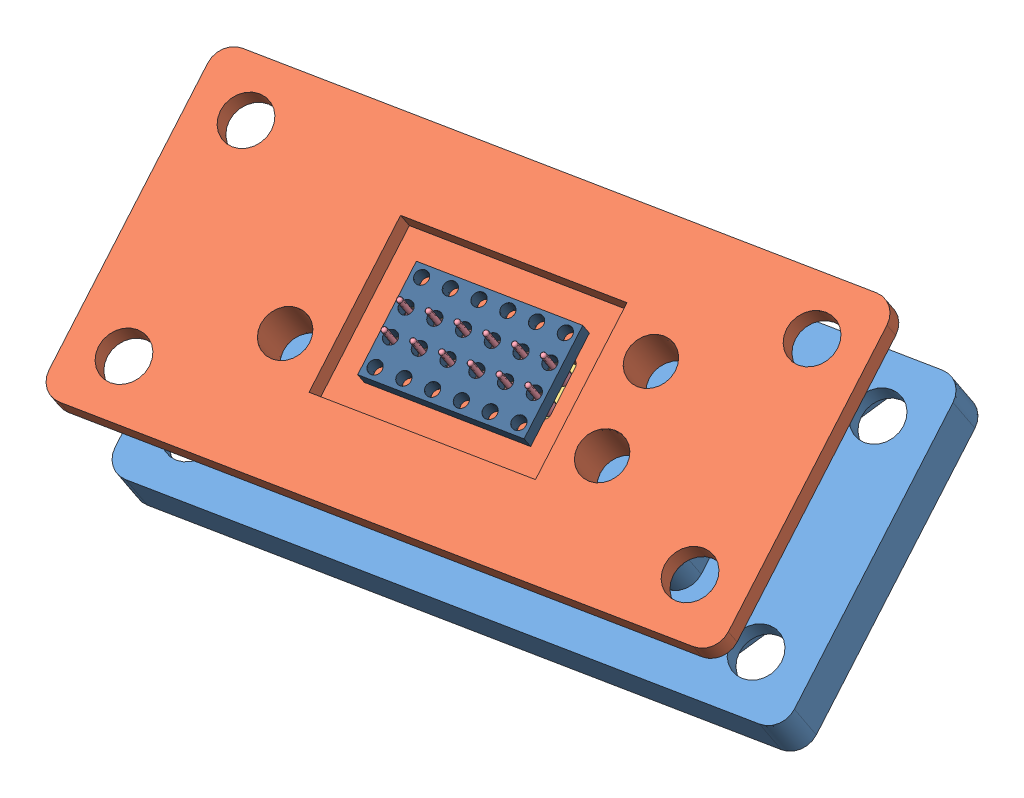
SolidWorks assembly Pogo_Fixture_Assembly, configuration Default. Lengths in mm.
Overall size (65.95 34.01 47.24).
138 component instances, 16 part files, 25 mates.
Components (placement in the parent):
- Pogo_Fixture_Male-2: Pogo_Fixture_Male [Default] at (19.7314 -83.9194 -57.5344) x (0.980151 -0.002673 -0.198236) z (-0.118444 -0.809738 -0.574714) size (60 30 8.18)
- Pogo_Fixture_Female-2: Pogo_Fixture_Female [Default] at (21.2786 -73.3423 -50.0273) x (-0.980151 0.002673 0.198236) z (0.118444 0.809738 0.574714) size (60 30 5.17)
- mill-max-419-10-212-00-001000-1: mill-max-419-10-212-00-001000 [Default] at (13.2092 -75.2259 -53.0027) x (0.980151 -0.002673 -0.198236) z (-0.158982 0.586786 -0.793982) size (15.24 7.37 5.08)
  - mill-max-419-10-212-00-001000_P4XX-21-010-00-000000-1: mill-max-419-10-212-00-001000_P4XX-21-010-00-000000 [Default] at origin size (15.24 2.79 5.08)
  - mill-max-419-10-212-00-001000_1942-1: mill-max-419-10-212-00-001000_1942 [Default] at (0.9644 0 -1.27) x (0 -1 0) z (0 0 1) size (7.37 1.78 1.78)
  - mill-max-419-10-212-00-001000_1942-2: mill-max-419-10-212-00-001000_1942 [Default] at (0.9644 0 -3.81) x (0 -1 0) z (0 0 1) size (7.37 1.78 1.78)
  - mill-max-419-10-212-00-001000_1942-3: mill-max-419-10-212-00-001000_1942 [Default] at (3.5044 0 -3.81) x (0 -1 0) z (0 0 1) size (7.37 1.78 1.78)
  - mill-max-419-10-212-00-001000_1942-4: mill-max-419-10-212-00-001000_1942 [Default] at (3.5044 0 -1.27) x (0 -1 0) z (0 0 1) size (7.37 1.78 1.78)
  - mill-max-419-10-212-00-001000_1942-5: mill-max-419-10-212-00-001000_1942 [Default] at (6.0444 0 -3.81) x (0 -1 0) z (0 0 1) size (7.37 1.78 1.78)
  - mill-max-419-10-212-00-001000_1942-6: mill-max-419-10-212-00-001000_1942 [Default] at (8.5844 0 -3.81) x (0 -1 0) z (0 0 1) size (7.37 1.78 1.78)
  - mill-max-419-10-212-00-001000_1942-7: mill-max-419-10-212-00-001000_1942 [Default] at (11.1244 0 -3.81) x (0 -1 0) z (0 0 1) size (7.37 1.78 1.78)
  - mill-max-419-10-212-00-001000_1942-8: mill-max-419-10-212-00-001000_1942 [Default] at (13.6644 0 -3.81) x (0 -1 0) z (0 0 1) size (7.37 1.78 1.78)
  - mill-max-419-10-212-00-001000_1942-9: mill-max-419-10-212-00-001000_1942 [Default] at (6.0444 0 -1.27) x (0 -1 0) z (0 0 1) size (7.37 1.78 1.78)
  - mill-max-419-10-212-00-001000_1942-10: mill-max-419-10-212-00-001000_1942 [Default] at (8.5844 0 -1.27) x (0 -1 0) z (0 0 1) size (7.37 1.78 1.78)
  - mill-max-419-10-212-00-001000_1942-11: mill-max-419-10-212-00-001000_1942 [Default] at (11.1244 0 -1.27) x (0 -1 0) z (0 0 1) size (7.37 1.78 1.78)
  - mill-max-419-10-212-00-001000_1942-12: mill-max-419-10-212-00-001000_1942 [Default] at (13.6644 0 -1.27) x (0 -1 0) z (0 0 1) size (7.37 1.78 1.78)
- mill-max-818-22-012-10-000101-1: mill-max-818-22-012-10-000101 [Default] at (12.9898 -85.228 -53.9526) x (0.980151 -0.002673 -0.198236) z (0.158982 -0.586786 0.793982) size (15.24 8.23 5.08)
  - mill-max-818-22-012-10-000101_P4XX-28-010-00-090000-1: mill-max-818-22-012-10-000101_P4XX-28-010-00-090000 [Default] at origin size (15.24 2.79 5.08)
  - mill-max-818-22-012-10-000101_0963-0-1: mill-max-818-22-012-10-000101_0963-0 [Default] at (0.9644 -4.953 -1.27) x (0 1 0) z (0 0 1) size (4.04 1.31 1.31)
  - mill-max-818-22-012-10-000101_0954-0-1: mill-max-818-22-012-10-000101_0954-0 [Default] at (0.9644 -3.2004 -1.27) x (0 1 0) z (-0.856247 0 0.516567) size (5.03 1.83 1.83)
  - mill-max-818-22-012-10-000101_0918-X-1: mill-max-818-22-012-10-000101_0918-X [Default] at (0.9644 -1.2192 -1.27) x (0 1 0) z (0 0 1) size (4.5 1.25 1.25)
  - mill-max-818-22-012-10-000101_6875-0-00-00-75-XX-43-0C-1: mill-max-818-22-012-10-000101_6875-0-00-00-75-XX-43-0C [Default] at (0.9644 0.6355 -1.27) x (-0.956034 0 -0.293257) z (0 -1 0) size (0.2 0.07 3.45)
  - mill-max-818-22-012-10-000101_0963-0-2: mill-max-818-22-012-10-000101_0963-0 [Default] at (0.9644 -4.953 -3.81) x (0 1 0) z (0 0 1) size (4.04 1.31 1.31)
  - mill-max-818-22-012-10-000101_0954-0-2: mill-max-818-22-012-10-000101_0954-0 [Default] at (0.9644 -3.2004 -3.81) x (0 1 0) z (0.135119 0 0.990829) size (5.03 1.83 1.83)
  - mill-max-818-22-012-10-000101_0918-X-2: mill-max-818-22-012-10-000101_0918-X [Default] at (0.9644 -1.2192 -3.81) x (0 1 0) z (0.012366 0 0.999924) size (4.5 1.25 1.25)
  - mill-max-818-22-012-10-000101_6875-0-00-00-75-XX-43-0C-2: mill-max-818-22-012-10-000101_6875-0-00-00-75-XX-43-0C [Default] at (0.9644 0.6358 -1.27) x (-0.954499 0 -0.298214) z (0 -1 0) size (0.2 0.07 3.45)
  - mill-max-818-22-012-10-000101_6875-0-00-00-75-XX-43-0C-3: mill-max-818-22-012-10-000101_6875-0-00-00-75-XX-43-0C [Default] at (3.5044 0.6358 -1.27) x (-0.954499 0 -0.298214) z (0 -1 0) size (0.2 0.07 3.45)
  - mill-max-818-22-012-10-000101_0918-X-3: mill-max-818-22-012-10-000101_0918-X [Default] at (3.5044 -1.2192 -3.81) x (0 1 0) z (0.012366 0 0.999924) size (4.5 1.25 1.25)
  - mill-max-818-22-012-10-000101_0954-0-3: mill-max-818-22-012-10-000101_0954-0 [Default] at (3.5044 -3.2004 -3.81) x (0 1 0) z (0.135119 0 0.990829) size (5.03 1.83 1.83)
  - mill-max-818-22-012-10-000101_0963-0-3: mill-max-818-22-012-10-000101_0963-0 [Default] at (3.5044 -4.953 -3.81) x (0 1 0) z (0 0 1) size (4.04 1.31 1.31)
  - mill-max-818-22-012-10-000101_6875-0-00-00-75-XX-43-0C-4: mill-max-818-22-012-10-000101_6875-0-00-00-75-XX-43-0C [Default] at (3.5044 0.6355 -1.27) x (-0.956034 0 -0.293257) z (0 -1 0) size (0.2 0.07 3.45)
  - mill-max-818-22-012-10-000101_0918-X-4: mill-max-818-22-012-10-000101_0918-X [Default] at (3.5044 -1.2192 -1.27) x (0 1 0) z (0 0 1) size (4.5 1.25 1.25)
  - mill-max-818-22-012-10-000101_0954-0-4: mill-max-818-22-012-10-000101_0954-0 [Default] at (3.5044 -3.2004 -1.27) x (0 1 0) z (-0.856247 0 0.516567) size (5.03 1.83 1.83)
  - mill-max-818-22-012-10-000101_0963-0-4: mill-max-818-22-012-10-000101_0963-0 [Default] at (3.5044 -4.953 -1.27) x (0 1 0) z (0 0 1) size (4.04 1.31 1.31)
  - mill-max-818-22-012-10-000101_6875-0-00-00-75-XX-43-0C-5: mill-max-818-22-012-10-000101_6875-0-00-00-75-XX-43-0C [Default] at (6.0444 0.6358 -1.27) x (-0.954499 0 -0.298214) z (0 -1 0) size (0.2 0.07 3.45)
  - mill-max-818-22-012-10-000101_6875-0-00-00-75-XX-43-0C-6: mill-max-818-22-012-10-000101_6875-0-00-00-75-XX-43-0C [Default] at (8.5844 0.6358 -1.27) x (-0.954499 0 -0.298214) z (0 -1 0) size (0.2 0.07 3.45)
  - mill-max-818-22-012-10-000101_6875-0-00-00-75-XX-43-0C-7: mill-max-818-22-012-10-000101_6875-0-00-00-75-XX-43-0C [Default] at (11.1244 0.6358 -1.27) x (-0.954499 0 -0.298214) z (0 -1 0) size (0.2 0.07 3.45)
  - mill-max-818-22-012-10-000101_6875-0-00-00-75-XX-43-0C-8: mill-max-818-22-012-10-000101_6875-0-00-00-75-XX-43-0C [Default] at (13.6644 0.6358 -1.27) x (-0.954499 0 -0.298214) z (0 -1 0) size (0.2 0.07 3.45)
  - mill-max-818-22-012-10-000101_0918-X-5: mill-max-818-22-012-10-000101_0918-X [Default] at (6.0444 -1.2192 -3.81) x (0 1 0) z (0.012366 0 0.999924) size (4.5 1.25 1.25)
  - mill-max-818-22-012-10-000101_0918-X-6: mill-max-818-22-012-10-000101_0918-X [Default] at (8.5844 -1.2192 -3.81) x (0 1 0) z (0.012366 0 0.999924) size (4.5 1.25 1.25)
  - mill-max-818-22-012-10-000101_0918-X-7: mill-max-818-22-012-10-000101_0918-X [Default] at (11.1244 -1.2192 -3.81) x (0 1 0) z (0.012366 0 0.999924) size (4.5 1.25 1.25)
  - mill-max-818-22-012-10-000101_0918-X-8: mill-max-818-22-012-10-000101_0918-X [Default] at (13.6644 -1.2192 -3.81) x (0 1 0) z (0.012366 0 0.999924) size (4.5 1.25 1.25)
  - mill-max-818-22-012-10-000101_0954-0-5: mill-max-818-22-012-10-000101_0954-0 [Default] at (6.0444 -3.2004 -3.81) x (0 1 0) z (0.135119 0 0.990829) size (5.03 1.83 1.83)
  - mill-max-818-22-012-10-000101_0954-0-6: mill-max-818-22-012-10-000101_0954-0 [Default] at (8.5844 -3.2004 -3.81) x (0 1 0) z (0.135119 0 0.990829) size (5.03 1.83 1.83)
  - mill-max-818-22-012-10-000101_0954-0-7: mill-max-818-22-012-10-000101_0954-0 [Default] at (11.1244 -3.2004 -3.81) x (0 1 0) z (0.135119 0 0.990829) size (5.03 1.83 1.83)
  - mill-max-818-22-012-10-000101_0954-0-8: mill-max-818-22-012-10-000101_0954-0 [Default] at (13.6644 -3.2004 -3.81) x (0 1 0) z (0.135119 0 0.990829) size (5.03 1.83 1.83)
  - mill-max-818-22-012-10-000101_0963-0-5: mill-max-818-22-012-10-000101_0963-0 [Default] at (6.0444 -4.953 -3.81) x (0 1 0) z (0 0 1) size (4.04 1.31 1.31)
  - mill-max-818-22-012-10-000101_0963-0-6: mill-max-818-22-012-10-000101_0963-0 [Default] at (8.5844 -4.953 -3.81) x (0 1 0) z (0 0 1) size (4.04 1.31 1.31)
  - mill-max-818-22-012-10-000101_0963-0-7: mill-max-818-22-012-10-000101_0963-0 [Default] at (11.1244 -4.953 -3.81) x (0 1 0) z (0 0 1) size (4.04 1.31 1.31)
  - mill-max-818-22-012-10-000101_0963-0-8: mill-max-818-22-012-10-000101_0963-0 [Default] at (13.6644 -4.953 -3.81) x (0 1 0) z (0 0 1) size (4.04 1.31 1.31)
  - mill-max-818-22-012-10-000101_6875-0-00-00-75-XX-43-0C-9: mill-max-818-22-012-10-000101_6875-0-00-00-75-XX-43-0C [Default] at (6.0444 0.6355 -1.27) x (-0.956034 0 -0.293257) z (0 -1 0) size (0.2 0.07 3.45)
  - mill-max-818-22-012-10-000101_6875-0-00-00-75-XX-43-0C-10: mill-max-818-22-012-10-000101_6875-0-00-00-75-XX-43-0C [Default] at (8.5844 0.6355 -1.27) x (-0.956034 0 -0.293257) z (0 -1 0) size (0.2 0.07 3.45)
  - mill-max-818-22-012-10-000101_6875-0-00-00-75-XX-43-0C-11: mill-max-818-22-012-10-000101_6875-0-00-00-75-XX-43-0C [Default] at (11.1244 0.6355 -1.27) x (-0.956034 0 -0.293257) z (0 -1 0) size (0.2 0.07 3.45)
  - mill-max-818-22-012-10-000101_6875-0-00-00-75-XX-43-0C-12: mill-max-818-22-012-10-000101_6875-0-00-00-75-XX-43-0C [Default] at (13.6644 0.6355 -1.27) x (-0.956034 0 -0.293257) z (0 -1 0) size (0.2 0.07 3.45)
  - mill-max-818-22-012-10-000101_0918-X-9: mill-max-818-22-012-10-000101_0918-X [Default] at (6.0444 -1.2192 -1.27) x (0 1 0) z (0 0 1) size (4.5 1.25 1.25)
  - mill-max-818-22-012-10-000101_0918-X-10: mill-max-818-22-012-10-000101_0918-X [Default] at (8.5844 -1.2192 -1.27) x (0 1 0) z (0 0 1) size (4.5 1.25 1.25)
  - mill-max-818-22-012-10-000101_0918-X-11: mill-max-818-22-012-10-000101_0918-X [Default] at (11.1244 -1.2192 -1.27) x (0 1 0) z (0 0 1) size (4.5 1.25 1.25)
  - mill-max-818-22-012-10-000101_0918-X-12: mill-max-818-22-012-10-000101_0918-X [Default] at (13.6644 -1.2192 -1.27) x (0 1 0) z (0 0 1) size (4.5 1.25 1.25)
  - mill-max-818-22-012-10-000101_0954-0-9: mill-max-818-22-012-10-000101_0954-0 [Default] at (6.0444 -3.2004 -1.27) x (0 1 0) z (-0.856247 0 0.516567) size (5.03 1.83 1.83)
  - mill-max-818-22-012-10-000101_0954-0-10: mill-max-818-22-012-10-000101_0954-0 [Default] at (8.5844 -3.2004 -1.27) x (0 1 0) z (-0.856247 0 0.516567) size (5.03 1.83 1.83)
  - mill-max-818-22-012-10-000101_0954-0-11: mill-max-818-22-012-10-000101_0954-0 [Default] at (11.1244 -3.2004 -1.27) x (0 1 0) z (-0.856247 0 0.516567) size (5.03 1.83 1.83)
  - mill-max-818-22-012-10-000101_0954-0-12: mill-max-818-22-012-10-000101_0954-0 [Default] at (13.6644 -3.2004 -1.27) x (0 1 0) z (-0.856247 0 0.516567) size (5.03 1.83 1.83)
  - mill-max-818-22-012-10-000101_0963-0-9: mill-max-818-22-012-10-000101_0963-0 [Default] at (6.0444 -4.953 -1.27) x (0 1 0) z (0 0 1) size (4.04 1.31 1.31)
  - mill-max-818-22-012-10-000101_0963-0-10: mill-max-818-22-012-10-000101_0963-0 [Default] at (8.5844 -4.953 -1.27) x (0 1 0) z (0 0 1) size (4.04 1.31 1.31)
  - mill-max-818-22-012-10-000101_0963-0-11: mill-max-818-22-012-10-000101_0963-0 [Default] at (11.1244 -4.953 -1.27) x (0 1 0) z (0 0 1) size (4.04 1.31 1.31)
  - mill-max-818-22-012-10-000101_0963-0-12: mill-max-818-22-012-10-000101_0963-0 [Default] at (13.6644 -4.953 -1.27) x (0 1 0) z (0 0 1) size (4.04 1.31 1.31)
- Perf_Board-1: Perf_Board [Default] at (21.2786 -73.3423 -50.0273) x (-0.980151 0.002673 0.198236) z (-0.158982 0.586786 -0.793982) size (14.7 1.5 9.62)
- Perf_Board-2: Perf_Board [Default] at (19.3761 -86.3486 -59.2586) x (-0.980151 0.002673 0.198236) z (0.158982 -0.586786 0.793982) size (14.7 1.5 9.62)
- Dowel_Pin_93600A123-1: Dowel_Pin_93600A123 [93600A123] at (34.5158 -83.3889 -55.0648) x (0.118444 0.809738 0.574714) z (-0.037614 -0.574714 0.81749) size (7.2 4 4)
- Dowel_Pin_93600A123-2: Dowel_Pin_93600A123 [93600A123] at (7.0716 -83.3141 -49.5142) x (0.118444 0.809738 0.574714) z (-0.037614 -0.574714 0.81749) size (7.2 4 4)
- Dowel_Pin_93600A123-3: Dowel_Pin_93600A123 [93600A123] at (33.244 -78.6946 -61.4167) x (0.118444 0.809738 0.574714) z (-0.037614 -0.574714 0.81749) size (7.2 4 4)
- mill-max-823-22-016-10-004101-1: mill-max-823-22-016-10-004101 [Default] at (10.7814 -85.6809 -52.8594) x (0.980151 -0.002673 -0.198236) z (0.158982 -0.586786 0.793982) size (20.32 7.75 5.08)
  - mill-max-823-22-016-10-004101_P4XX-28-010-00-090000-1: mill-max-823-22-016-10-004101_P4XX-28-010-00-090000 [Default] at origin size (20.32 2.79 5.08)
  - mill-max-823-22-016-10-004101_0963-0-1: mill-max-823-22-016-10-004101_0963-0 [Default] at (0.9644 -4.953 -1.27) x (0 1 0) z (0 0 1) size (4.04 1.31 1.31)
  - mill-max-823-22-016-10-004101_0953-X-1: mill-max-823-22-016-10-004101_0953-X [Default] at (0.9644 -3.2004 -1.27) x (0 1 0) z (-0.980895 0 0.194537) size (2.69 1.83 1.83)
  - mill-max-823-22-016-10-004101_0918-X-1: mill-max-823-22-016-10-004101_0918-X [Default] at (0.9644 -1.1938 -1.27) x (0 1 0) z (0 0 1) size (3.99 1.25 1.25)
  - mill-max-823-22-016-10-004101_6875-0-00-00-75-XX-43-0C-1: mill-max-823-22-016-10-004101_6875-0-00-00-75-XX-43-0C [Default] at (0.9644 0.6557 -1.27) x (-0.956034 0 -0.293257) z (0 -1 0) size (0.2 0.07 3.45)
  - mill-max-823-22-016-10-004101_0963-0-2: mill-max-823-22-016-10-004101_0963-0 [Default] at (0.9644 -4.953 -3.81) x (0 1 0) z (0 0 1) size (4.04 1.31 1.31)
  - mill-max-823-22-016-10-004101_0953-X-2: mill-max-823-22-016-10-004101_0953-X [Default] at (0.9644 -3.2004 -3.81) x (0 1 0) z (0 0 1) size (2.69 1.83 1.83)
  - mill-max-823-22-016-10-004101_0918-X-2: mill-max-823-22-016-10-004101_0918-X [Default] at (0.9644 -1.1938 -3.81) x (0 1 0) z (0.012366 0 0.999924) size (3.99 1.25 1.25)
  - mill-max-823-22-016-10-004101_6875-0-00-00-75-XX-43-0C-2: mill-max-823-22-016-10-004101_6875-0-00-00-75-XX-43-0C [Default] at (0.9644 -2.5164 -3.81) x (-0.692815 0 0.721116) z (0 1 0) size (0.2 0.07 3.45)
  - mill-max-823-22-016-10-004101_6875-0-00-00-75-XX-43-0C-3: mill-max-823-22-016-10-004101_6875-0-00-00-75-XX-43-0C [Default] at (3.5044 -2.5164 -3.81) x (-0.692815 0 0.721116) z (0 1 0) size (0.2 0.07 3.45)
  - mill-max-823-22-016-10-004101_0918-X-3: mill-max-823-22-016-10-004101_0918-X [Default] at (3.5044 -1.1938 -3.81) x (0 1 0) z (0.012366 0 0.999924) size (3.99 1.25 1.25)
  - mill-max-823-22-016-10-004101_0953-X-3: mill-max-823-22-016-10-004101_0953-X [Default] at (3.5044 -3.2004 -3.81) x (0 1 0) z (0 0 1) size (2.69 1.83 1.83)
  - mill-max-823-22-016-10-004101_0963-0-3: mill-max-823-22-016-10-004101_0963-0 [Default] at (3.5044 -4.953 -3.81) x (0 1 0) z (0 0 1) size (4.04 1.31 1.31)
  - mill-max-823-22-016-10-004101_6875-0-00-00-75-XX-43-0C-4: mill-max-823-22-016-10-004101_6875-0-00-00-75-XX-43-0C [Default] at (3.5044 0.6557 -1.27) x (-0.956034 0 -0.293257) z (0 -1 0) size (0.2 0.07 3.45)
  - mill-max-823-22-016-10-004101_0918-X-4: mill-max-823-22-016-10-004101_0918-X [Default] at (3.5044 -1.1938 -1.27) x (0 1 0) z (0 0 1) size (3.99 1.25 1.25)
  - mill-max-823-22-016-10-004101_0953-X-4: mill-max-823-22-016-10-004101_0953-X [Default] at (3.5044 -3.2004 -1.27) x (0 1 0) z (-0.980895 0 0.194537) size (2.69 1.83 1.83)
  - mill-max-823-22-016-10-004101_0963-0-4: mill-max-823-22-016-10-004101_0963-0 [Default] at (3.5044 -4.953 -1.27) x (0 1 0) z (0 0 1) size (4.04 1.31 1.31)
  - mill-max-823-22-016-10-004101_6875-0-00-00-75-XX-43-0C-5: mill-max-823-22-016-10-004101_6875-0-00-00-75-XX-43-0C [Default] at (6.0444 -2.5164 -3.81) x (-0.692815 0 0.721116) z (0 1 0) size (0.2 0.07 3.45)
  - mill-max-823-22-016-10-004101_6875-0-00-00-75-XX-43-0C-6: mill-max-823-22-016-10-004101_6875-0-00-00-75-XX-43-0C [Default] at (8.5844 -2.5164 -3.81) x (-0.692815 0 0.721116) z (0 1 0) size (0.2 0.07 3.45)
  - mill-max-823-22-016-10-004101_6875-0-00-00-75-XX-43-0C-7: mill-max-823-22-016-10-004101_6875-0-00-00-75-XX-43-0C [Default] at (11.1244 -2.5164 -3.81) x (-0.692815 0 0.721116) z (0 1 0) size (0.2 0.07 3.45)
  - mill-max-823-22-016-10-004101_6875-0-00-00-75-XX-43-0C-8: mill-max-823-22-016-10-004101_6875-0-00-00-75-XX-43-0C [Default] at (13.6644 -2.5164 -3.81) x (-0.692815 0 0.721116) z (0 1 0) size (0.2 0.07 3.45)
  - mill-max-823-22-016-10-004101_6875-0-00-00-75-XX-43-0C-9: mill-max-823-22-016-10-004101_6875-0-00-00-75-XX-43-0C [Default] at (16.2044 -2.5164 -3.81) x (-0.692815 0 0.721116) z (0 1 0) size (0.2 0.07 3.45)
  - mill-max-823-22-016-10-004101_6875-0-00-00-75-XX-43-0C-10: mill-max-823-22-016-10-004101_6875-0-00-00-75-XX-43-0C [Default] at (18.7444 -2.5164 -3.81) x (-0.692815 0 0.721116) z (0 1 0) size (0.2 0.07 3.45)
  - mill-max-823-22-016-10-004101_0918-X-5: mill-max-823-22-016-10-004101_0918-X [Default] at (6.0444 -1.1938 -3.81) x (0 1 0) z (0.012366 0 0.999924) size (3.99 1.25 1.25)
  - mill-max-823-22-016-10-004101_0918-X-6: mill-max-823-22-016-10-004101_0918-X [Default] at (8.5844 -1.1938 -3.81) x (0 1 0) z (0.012366 0 0.999924) size (3.99 1.25 1.25)
  - mill-max-823-22-016-10-004101_0918-X-7: mill-max-823-22-016-10-004101_0918-X [Default] at (11.1244 -1.1938 -3.81) x (0 1 0) z (0.012366 0 0.999924) size (3.99 1.25 1.25)
  - mill-max-823-22-016-10-004101_0918-X-8: mill-max-823-22-016-10-004101_0918-X [Default] at (13.6644 -1.1938 -3.81) x (0 1 0) z (0.012366 0 0.999924) size (3.99 1.25 1.25)
  - mill-max-823-22-016-10-004101_0918-X-9: mill-max-823-22-016-10-004101_0918-X [Default] at (16.2044 -1.1938 -3.81) x (0 1 0) z (0.012366 0 0.999924) size (3.99 1.25 1.25)
  - mill-max-823-22-016-10-004101_0918-X-10: mill-max-823-22-016-10-004101_0918-X [Default] at (18.7444 -1.1938 -3.81) x (0 1 0) z (0.012366 0 0.999924) size (3.99 1.25 1.25)
  - mill-max-823-22-016-10-004101_0953-X-5: mill-max-823-22-016-10-004101_0953-X [Default] at (6.0444 -3.2004 -3.81) x (0 1 0) z (0 0 1) size (2.69 1.83 1.83)
  - mill-max-823-22-016-10-004101_0953-X-6: mill-max-823-22-016-10-004101_0953-X [Default] at (8.5844 -3.2004 -3.81) x (0 1 0) z (0 0 1) size (2.69 1.83 1.83)
  - mill-max-823-22-016-10-004101_0953-X-7: mill-max-823-22-016-10-004101_0953-X [Default] at (11.1244 -3.2004 -3.81) x (0 1 0) z (0 0 1) size (2.69 1.83 1.83)
  - mill-max-823-22-016-10-004101_0953-X-8: mill-max-823-22-016-10-004101_0953-X [Default] at (13.6644 -3.2004 -3.81) x (0 1 0) z (0 0 1) size (2.69 1.83 1.83)
  - mill-max-823-22-016-10-004101_0953-X-9: mill-max-823-22-016-10-004101_0953-X [Default] at (16.2044 -3.2004 -3.81) x (0 1 0) z (0 0 1) size (2.69 1.83 1.83)
  - mill-max-823-22-016-10-004101_0953-X-10: mill-max-823-22-016-10-004101_0953-X [Default] at (18.7444 -3.2004 -3.81) x (0 1 0) z (0 0 1) size (2.69 1.83 1.83)
  - mill-max-823-22-016-10-004101_0963-0-5: mill-max-823-22-016-10-004101_0963-0 [Default] at (6.0444 -4.953 -3.81) x (0 1 0) z (0 0 1) size (4.04 1.31 1.31)
  - mill-max-823-22-016-10-004101_0963-0-6: mill-max-823-22-016-10-004101_0963-0 [Default] at (8.5844 -4.953 -3.81) x (0 1 0) z (0 0 1) size (4.04 1.31 1.31)
  - mill-max-823-22-016-10-004101_0963-0-7: mill-max-823-22-016-10-004101_0963-0 [Default] at (11.1244 -4.953 -3.81) x (0 1 0) z (0 0 1) size (4.04 1.31 1.31)
  - mill-max-823-22-016-10-004101_0963-0-8: mill-max-823-22-016-10-004101_0963-0 [Default] at (13.6644 -4.953 -3.81) x (0 1 0) z (0 0 1) size (4.04 1.31 1.31)
  - mill-max-823-22-016-10-004101_0963-0-9: mill-max-823-22-016-10-004101_0963-0 [Default] at (16.2044 -4.953 -3.81) x (0 1 0) z (0 0 1) size (4.04 1.31 1.31)
  - mill-max-823-22-016-10-004101_0963-0-10: mill-max-823-22-016-10-004101_0963-0 [Default] at (18.7444 -4.953 -3.81) x (0 1 0) z (0 0 1) size (4.04 1.31 1.31)
  - mill-max-823-22-016-10-004101_6875-0-00-00-75-XX-43-0C-11: mill-max-823-22-016-10-004101_6875-0-00-00-75-XX-43-0C [Default] at (6.0444 0.6557 -1.27) x (-0.956034 0 -0.293257) z (0 -1 0) size (0.2 0.07 3.45)
  - mill-max-823-22-016-10-004101_6875-0-00-00-75-XX-43-0C-12: mill-max-823-22-016-10-004101_6875-0-00-00-75-XX-43-0C [Default] at (8.5844 0.6557 -1.27) x (-0.956034 0 -0.293257) z (0 -1 0) size (0.2 0.07 3.45)
  - mill-max-823-22-016-10-004101_6875-0-00-00-75-XX-43-0C-13: mill-max-823-22-016-10-004101_6875-0-00-00-75-XX-43-0C [Default] at (11.1244 0.6557 -1.27) x (-0.956034 0 -0.293257) z (0 -1 0) size (0.2 0.07 3.45)
  - mill-max-823-22-016-10-004101_6875-0-00-00-75-XX-43-0C-14: mill-max-823-22-016-10-004101_6875-0-00-00-75-XX-43-0C [Default] at (13.6644 0.6557 -1.27) x (-0.956034 0 -0.293257) z (0 -1 0) size (0.2 0.07 3.45)
  - mill-max-823-22-016-10-004101_6875-0-00-00-75-XX-43-0C-15: mill-max-823-22-016-10-004101_6875-0-00-00-75-XX-43-0C [Default] at (16.2044 0.6557 -1.27) x (-0.956034 0 -0.293257) z (0 -1 0) size (0.2 0.07 3.45)
  - mill-max-823-22-016-10-004101_6875-0-00-00-75-XX-43-0C-16: mill-max-823-22-016-10-004101_6875-0-00-00-75-XX-43-0C [Default] at (18.7444 0.6557 -1.27) x (-0.956034 0 -0.293257) z (0 -1 0) size (0.2 0.07 3.45)
  - mill-max-823-22-016-10-004101_0918-X-11: mill-max-823-22-016-10-004101_0918-X [Default] at (6.0444 -1.1938 -1.27) x (0 1 0) z (0 0 1) size (3.99 1.25 1.25)
  - mill-max-823-22-016-10-004101_0918-X-12: mill-max-823-22-016-10-004101_0918-X [Default] at (8.5844 -1.1938 -1.27) x (0 1 0) z (0 0 1) size (3.99 1.25 1.25)
  - mill-max-823-22-016-10-004101_0918-X-13: mill-max-823-22-016-10-004101_0918-X [Default] at (11.1244 -1.1938 -1.27) x (0 1 0) z (0 0 1) size (3.99 1.25 1.25)
  - mill-max-823-22-016-10-004101_0918-X-14: mill-max-823-22-016-10-004101_0918-X [Default] at (13.6644 -1.1938 -1.27) x (0 1 0) z (0 0 1) size (3.99 1.25 1.25)
  - mill-max-823-22-016-10-004101_0918-X-15: mill-max-823-22-016-10-004101_0918-X [Default] at (16.2044 -1.1938 -1.27) x (0 1 0) z (0 0 1) size (3.99 1.25 1.25)
  - mill-max-823-22-016-10-004101_0918-X-16: mill-max-823-22-016-10-004101_0918-X [Default] at (18.7444 -1.1938 -1.27) x (0 1 0) z (0 0 1) size (3.99 1.25 1.25)
  - mill-max-823-22-016-10-004101_0953-X-11: mill-max-823-22-016-10-004101_0953-X [Default] at (6.0444 -3.2004 -1.27) x (0 1 0) z (-0.980895 0 0.194537) size (2.69 1.83 1.83)
  - mill-max-823-22-016-10-004101_0953-X-12: mill-max-823-22-016-10-004101_0953-X [Default] at (8.5844 -3.2004 -1.27) x (0 1 0) z (-0.980895 0 0.194537) size (2.69 1.83 1.83)
  - mill-max-823-22-016-10-004101_0953-X-13: mill-max-823-22-016-10-004101_0953-X [Default] at (11.1244 -3.2004 -1.27) x (0 1 0) z (-0.980895 0 0.194537) size (2.69 1.83 1.83)
  - mill-max-823-22-016-10-004101_0953-X-14: mill-max-823-22-016-10-004101_0953-X [Default] at (13.6644 -3.2004 -1.27) x (0 1 0) z (-0.980895 0 0.194537) size (2.69 1.83 1.83)
  - mill-max-823-22-016-10-004101_0953-X-15: mill-max-823-22-016-10-004101_0953-X [Default] at (16.2044 -3.2004 -1.27) x (0 1 0) z (-0.980895 0 0.194537) size (2.69 1.83 1.83)
  - mill-max-823-22-016-10-004101_0953-X-16: mill-max-823-22-016-10-004101_0953-X [Default] at (18.7444 -3.2004 -1.27) x (0 1 0) z (-0.980895 0 0.194537) size (2.69 1.83 1.83)
  - mill-max-823-22-016-10-004101_0963-0-11: mill-max-823-22-016-10-004101_0963-0 [Default] at (6.0444 -4.953 -1.27) x (0 1 0) z (0 0 1) size (4.04 1.31 1.31)
  - mill-max-823-22-016-10-004101_0963-0-12: mill-max-823-22-016-10-004101_0963-0 [Default] at (8.5844 -4.953 -1.27) x (0 1 0) z (0 0 1) size (4.04 1.31 1.31)
  - mill-max-823-22-016-10-004101_0963-0-13: mill-max-823-22-016-10-004101_0963-0 [Default] at (11.1244 -4.953 -1.27) x (0 1 0) z (0 0 1) size (4.04 1.31 1.31)
  - mill-max-823-22-016-10-004101_0963-0-14: mill-max-823-22-016-10-004101_0963-0 [Default] at (13.6644 -4.953 -1.27) x (0 1 0) z (0 0 1) size (4.04 1.31 1.31)
  - mill-max-823-22-016-10-004101_0963-0-15: mill-max-823-22-016-10-004101_0963-0 [Default] at (16.2044 -4.953 -1.27) x (0 1 0) z (0 0 1) size (4.04 1.31 1.31)
  - mill-max-823-22-016-10-004101_0963-0-16: mill-max-823-22-016-10-004101_0963-0 [Default] at (18.7444 -4.953 -1.27) x (0 1 0) z (0 0 1) size (4.04 1.31 1.31)
- Dowel_Pin_93600A123-5: Dowel_Pin_93600A123 [93600A123] at (5.7998 -78.6198 -55.8661) x (0.118444 0.809738 0.574714) z (-0.037614 -0.574714 0.81749) size (7.2 4 4)
Mates (geometry in assembly coordinates):
- Coincident2: coincident anti-aligned: plane of mill-max-419-10-212-00-001000-1/mill-max-419-10-212-00-001000_1942-12 through (26.9101 -72.8918 -51.8226) normal (0.118444 0.809738 0.574714); plane of Perf_Board-1 through (21.2786 -73.3423 -50.0273) normal (-0.118444 -0.809738 -0.574714)
- Concentric1: concentric aligned: cylinder of mill-max-419-10-212-00-001000-1/mill-max-419-10-212-00-001000_1942-12 through (27.6466 -70.2488 -50.6157) axis (-0.118444 -0.809738 -0.574714) radius 0.254; cylinder of Perf_Board-1 through (27.4783 -71.3995 -51.4324) axis (-0.118444 -0.809738 -0.574714) radius 0.635
- Concentric2: concentric aligned: cylinder of mill-max-419-10-212-00-001000-1/mill-max-419-10-212-00-001000_1942-8 through (28.0504 -71.7393 -48.599) axis (-0.118444 -0.809738 -0.574714) radius 0.254; cylinder of Perf_Board-1 through (27.8821 -72.8899 -49.4157) axis (-0.118444 -0.809738 -0.574714) radius 0.635
- Coincident3: coincident anti-aligned: plane of mill-max-818-22-012-10-000101-1/mill-max-818-22-012-10-000101_0954-0-5 through (19.0765 -86.0674 -59.593) normal (-0.118444 -0.809738 -0.574714); plane of Perf_Board-2 through (19.3761 -86.3486 -59.2586) normal (0.118444 0.809738 0.574714)
- Concentric3: concentric anti-aligned: cylinder of mill-max-818-22-012-10-000101-1/mill-max-818-22-012-10-000101_0963-0-8 through (25.3891 -85.6821 -61.5695) axis (-0.118444 -0.809738 -0.574714) radius 0.2159; cylinder of Perf_Board-2 through (25.2204 -86.835 -62.3878) axis (0.118444 0.809738 0.574714) radius 0.635
- Concentric4: concentric anti-aligned: cylinder of mill-max-818-22-012-10-000101-1/mill-max-818-22-012-10-000101_0963-0-12 through (25.7929 -87.1725 -59.5528) axis (-0.118444 -0.809738 -0.574714) radius 0.2159; cylinder of Perf_Board-2 through (25.6243 -88.3254 -60.3711) axis (0.118444 0.809738 0.574714) radius 0.635
- Coincident4: coincident anti-aligned: line of Pogo_Fixture_Female-2 through (1.4468 -73.2882 -46.0163) axis (0.980151 -0.002673 -0.198236); plane of Perf_Board-1 through (21.2786 -73.3423 -50.0273) normal (-0.118444 -0.809738 -0.574714)
- Concentric5: concentric anti-aligned: circle of Pogo_Fixture_Female-2; cylinder of mill-max-419-10-212-00-001000-1/mill-max-419-10-212-00-001000_1942-12 through (27.2765 -72.7786 -52.4112) axis (-0.118444 -0.809738 -0.574714) radius 0.6731
- Concentric6: concentric anti-aligned: circle of Pogo_Fixture_Female-2; cylinder of mill-max-419-10-212-00-001000-1/mill-max-419-10-212-00-001000_1942-11 through (24.787 -72.7718 -51.9077) axis (-0.118444 -0.809738 -0.574714) radius 0.6731
- Coincident5: coincident anti-aligned: plane of Pogo_Fixture_Male-2 through (19.3761 -86.3486 -59.2586) normal (-0.118444 -0.809738 -0.574714); plane of Perf_Board-2 through (19.3761 -86.3486 -59.2586) normal (0.118444 0.809738 0.574714)
- Concentric7: concentric aligned: circle of Pogo_Fixture_Male-2; cylinder of mill-max-818-22-012-10-000101-1/mill-max-818-22-012-10-000101_0954-0-12 through (25.8501 -86.7817 -59.2754) axis (-0.118444 -0.809738 -0.574714) radius 0.9144
- Concentric8: concentric anti-aligned: circle of Pogo_Fixture_Male-2; cylinder of Perf_Board-2 through (25.2204 -86.835 -62.3878) axis (0.118444 0.809738 0.574714) radius 0.635
- Parallel1: parallel anti-aligned: plane of Pogo_Fixture_Male-2 through (49.2424 -91.6225 -52.7633) normal (0.118444 0.809738 0.574714); plane of Pogo_Fixture_Female-2 through (-4.0989 -80.8957 -34.155) normal (-0.118444 -0.809738 -0.574714)
- Concentric9: concentric anti-aligned: cylinder of Pogo_Fixture_Male-2 through (33.4972 -90.3527 -60.0074) axis (-0.118444 -0.809738 -0.574714) radius 2.01; cylinder of Dowel_Pin_93600A123-1 through (34.1605 -85.8181 -56.789) axis (0.118444 0.809738 0.574714) radius 2
- Coincident9: coincident anti-aligned: plane of Pogo_Fixture_Male-2 through (49.2424 -91.6225 -52.7633) normal (0.118444 0.809738 0.574714); plane of Dowel_Pin_93600A123-1 through (34.0894 -86.304 -57.1338) normal (-0.118444 -0.809738 -0.574714)
- Coincident10: coincident anti-aligned: plane of Pogo_Fixture_Male-2 through (49.2424 -91.6225 -52.7633) normal (0.118444 0.809738 0.574714); plane of Dowel_Pin_93600A123-2 through (6.6452 -86.2291 -51.5832) normal (-0.118444 -0.809738 -0.574714)
- Concentric10: concentric anti-aligned: cylinder of Pogo_Fixture_Male-2 through (6.053 -90.2778 -54.4568) axis (-0.118444 -0.809738 -0.574714) radius 2.01; cylinder of Dowel_Pin_93600A123-2 through (6.7163 -85.7433 -51.2384) axis (0.118444 0.809738 0.574714) radius 2
- Concentric11: concentric anti-aligned: cylinder of Pogo_Fixture_Male-2 through (32.2254 -85.6584 -66.3592) axis (-0.118444 -0.809738 -0.574714) radius 2.01; cylinder of Dowel_Pin_93600A123-3 through (32.8886 -81.1238 -63.1408) axis (0.118444 0.809738 0.574714) radius 2
- Coincident11: coincident anti-aligned: plane of Pogo_Fixture_Male-2 through (49.2424 -91.6225 -52.7633) normal (0.118444 0.809738 0.574714); plane of Dowel_Pin_93600A123-3 through (32.8176 -81.6097 -63.4856) normal (-0.118444 -0.809738 -0.574714)
- Concentric13: concentric anti-aligned: cylinder of Pogo_Fixture_Female-2 through (8.4293 -74.0326 -42.9267) axis (-0.118444 -0.809738 -0.574714) radius 2.16; cylinder of Dowel_Pin_93600A123-2 through (6.7163 -85.7433 -51.2384) axis (0.118444 0.809738 0.574714) radius 2
- Concentric14: concentric anti-aligned: cylinder of Dowel_Pin_93600A123-1 through (34.1605 -85.8181 -56.789) axis (0.118444 0.809738 0.574714) radius 2; cylinder of Pogo_Fixture_Female-2 through (35.8735 -74.1074 -48.4773) axis (-0.118444 -0.809738 -0.574714) radius 2.16
- Coincident12: coincident aligned: plane of Pogo_Fixture_Male-2 through (19.3761 -86.3486 -59.2586) normal (-0.118444 -0.809738 -0.574714); plane of mill-max-823-22-016-10-004101-1/mill-max-823-22-016-10-004101_0953-X-1 through (10.6054 -88.166 -54.8904) normal (-0.118444 -0.809738 -0.574714)
- Coincident14: coincident anti-aligned: plane of Pogo_Fixture_Male-2 through (10.7669 -90.7228 -51.3213) normal (0.980151 -0.002673 -0.198236); plane of mill-max-823-22-016-10-004101-1/mill-max-823-22-016-10-004101_P4XX-28-010-00-090000-1 through (9.4069 -85.1963 -58.1204) normal (-0.980151 0.002673 0.198236)
- Coincident16: coincident anti-aligned: plane of Pogo_Fixture_Male-2 through (49.2424 -91.6225 -52.7633) normal (0.118444 0.809738 0.574714); plane of Dowel_Pin_93600A123-5 through (5.3734 -81.5348 -57.9351) normal (-0.118444 -0.809738 -0.574714)
- Concentric16: concentric aligned: cylinder of Pogo_Fixture_Male-2 through (4.7811 -85.5835 -60.8086) axis (0.118444 0.809738 0.574714) radius 2.01; cylinder of Dowel_Pin_93600A123-5 through (5.4444 -81.049 -57.5902) axis (0.118444 0.809738 0.574714) radius 2
